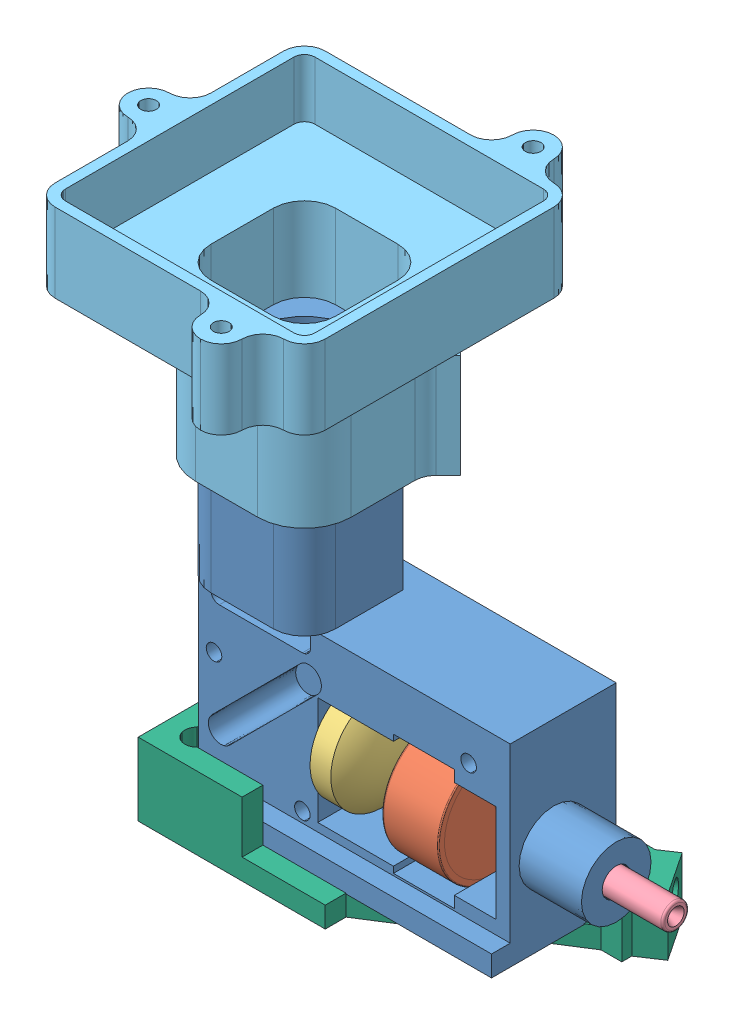
SolidWorks assembly 2CS Assembly, configuration Default. Lengths in mm.
Overall size (26.37 26.09 17).
7 component instances, 7 part files, 11 mates.
Components (placement in the parent):
- MS_MainBody_TwoColor-1: MS_MainBody_TwoColor [Default] at (6.7906 4.7158 11.136) size (18 18.3 6.5)
- step_16699-1: step_16699 [Default] at (7.8267 8.7158 11.136) x (1 0 0) z (0 0.216546 -0.976272) size (3.7 5.58 5.58)
- step_45228-1: step_45228 [Default] at (6.9305 8.7158 11.136) x (0 -0.095952 0.995386) z (-1 0 0) size (5 5 1.87)
- CFLC230-1: CFLC230 [Default] at (20.1576 8.7158 11.136) x (0 -0.264491 -0.964388) z (1 0 0) size (1.25 1.25 6.4)
- 2CS_MS_FilterCoverv3-2: 2CS_MS_FilterCoverv3 [Default] at (6.7906 9.8658 132.1798) x (-1 0 0) z (0 0 -1) size (15 8.3 1.4) (hidden)
- MS_FocusSliderv3.2-1: MS_FocusSliderv3.2 [Default] at (2.2906 19.0405 11.136) size (15 10.8 17)
- 2CS_MS_Baseplatev3-1: 2CS_MS_Baseplatev3 [Default] at (7.0406 3.7522 10.886) x (0 0 1) z (-1 0 0) size (9.02 3.5 18.54)
Mates (geometry in assembly coordinates):
- Concentric4: concentric anti-aligned: circle of CFLC230-1; cylinder of MS_MainBody_TwoColor-1 through (-2.6186 8.7158 11.136) axis (1 0 0) radius 0.675
- Coincident9: coincident aligned: plane of MS_MainBody_TwoColor-1 through (-0.7094 14.0158 8.136) normal (-1 0 0); plane of 2CS_MS_FilterCoverv3-2 through (-0.7094 14.0158 131.2798) normal (-1 0 0)
- Coincident10: coincident: point of MS_MainBody_TwoColor-1; plane of CFLC230-1 through (13.7576 8.7158 11.136) normal (-1 0 0)
- Concentric6: concentric anti-aligned: cylinder of MS_MainBody_TwoColor-1 through (11.6006 8.7158 11.136) axis (1 0 0) radius 2.9; cylinder of step_16699-1 through (11.7117 8.7158 11.136) axis (-1 0 0) radius 2.7925
- Concentric8: concentric anti-aligned: cylinder of MS_MainBody_TwoColor-1 through (11.6006 8.7158 11.136) axis (1 0 0) radius 2.6; cylinder of step_45228-1 through (6.0586 8.7158 11.136) axis (-1 0 0) radius 2.5
- Parallel2: parallel anti-aligned: plane of MS_MainBody_TwoColor-1 through (6.7906 14.0158 11.136) normal (0 1 0); plane of MS_FocusSliderv3.2-1 through (2.2906 19.0405 11.136) normal (0 -1 0)
- Coincident13: coincident anti-aligned: plane of MS_MainBody_TwoColor-1 through (14.2906 14.0158 14.136) normal (0 0 1); plane of MS_FocusSliderv3.2-1 through (-0.7094 29.8405 14.136) normal (0 0 -1)
- Coincident14: coincident anti-aligned: plane of MS_MainBody_TwoColor-1 through (-0.7094 14.0158 8.136) normal (-1 0 0); plane of MS_FocusSliderv3.2-1 through (-0.7094 29.8405 8.136) normal (1 0 0)
- Coincident17: coincident anti-aligned: plane of MS_MainBody_TwoColor-1 through (-0.7094 14.0158 8.136) normal (-1 0 0); plane of 2CS_MS_Baseplatev3-1 through (-0.7094 -13.0556 14.136) normal (1 0 0)
- Coincident18: coincident anti-aligned: plane of MS_MainBody_TwoColor-1 through (14.2906 14.0158 14.136) normal (0 0 1); plane of 2CS_MS_Baseplatev3-1 through (14.7906 -13.0556 14.136) normal (0 0 -1)
- Coincident19: coincident aligned: plane of MS_MainBody_TwoColor-1 through (6.7906 14.0158 11.136) normal (0 1 0); plane of 2CS_MS_FilterCoverv3-2 through (-0.7094 14.0158 131.2798) normal (0 1 0)
